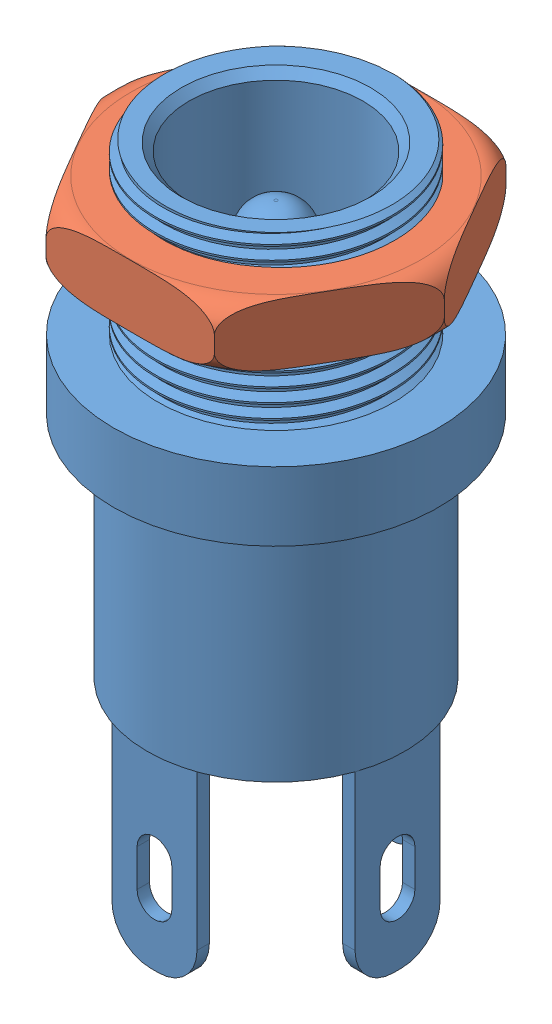
SolidWorks assembly 5.5mm 2.1mm DC JACK, configuration Default. Lengths in mm.
Overall size (11.46 21.74 10.67).
2 component instances, 2 part files, 2 mates.
Components (placement in the parent):
- JACK-1: JACK [Default] at origin size (10.67 21.74 10.67)
- NUT-1: NUT [Default] at (0 2.4716 0) size (11.46 2.43 9.98)
Mates (geometry in assembly coordinates):
- Concentric1: concentric aligned: cylinder of JACK-1 through (0 5.461 0) axis (0 -1 0) radius 3.8735; cylinder of NUT-1 through (0 4.5036 0) axis (0 -1 0) radius 3.6703
- LimitDistance1: limit distance = 2.4716 mm anti-aligned: plane of JACK-1 through (0 0 0) normal (0 1 0); plane of NUT-1 through (0 2.4716 0) normal (0 -1 0)
